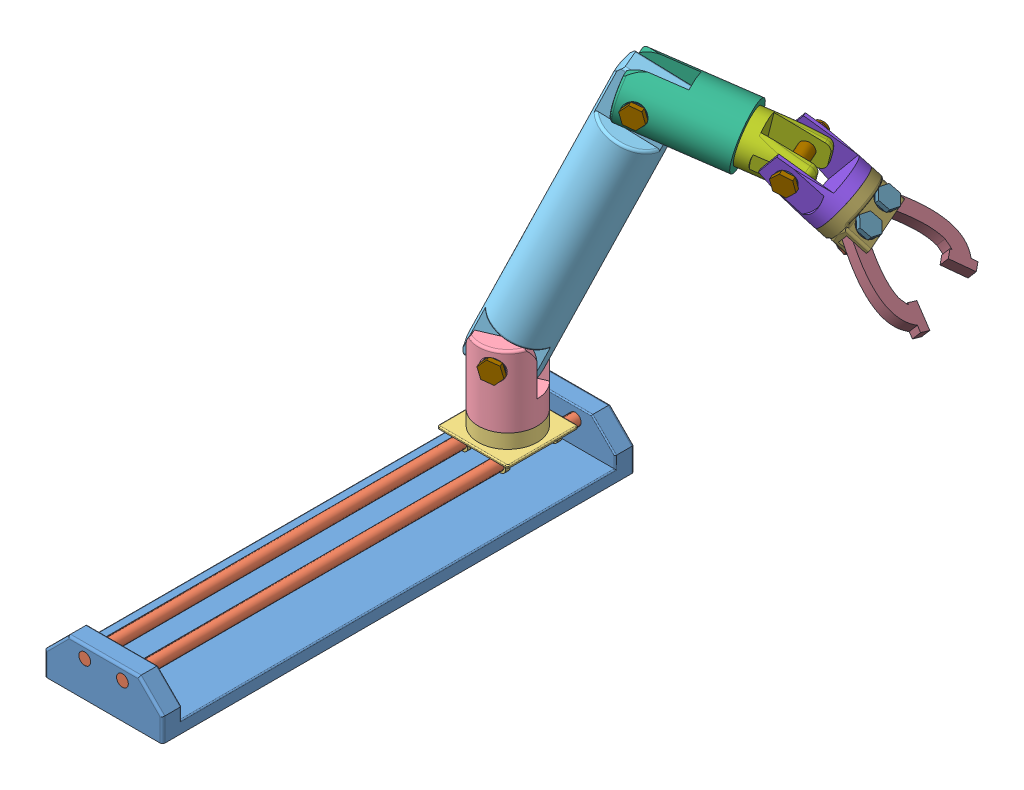
SolidWorks assembly Ensamble brazo, configuration Default. Lengths in mm.
Overall size (1624.77 1668.84 2538.17).
32 component instances, 14 part files, 63 mates.
Components (placement in the parent):
- Base brazo-1: Base brazo [Default] at (1021.9198 1533.4748 1057.1209) size (500 200 2000)
- Eje(s) de brazo-1: Eje(s) de brazo [Default] at (941.9198 1583.4748 1057.1209) x (0 0 1) z (-1 0 0) size (2000 49.9 49.9)
- Eje(s) de brazo-2: Eje(s) de brazo [Default] at (1101.9198 1583.4748 1057.1209) x (0 0 1) z (-1 0 0) size (2000 49.9 49.9)
- Plataforma brazo-1: Plataforma brazo [Default<As Machined>] at (1021.9198 1613.4748 1343.3712) x (1 0 0) z (0 1 0) size (300 300 189.9)
- brazo 1-1: brazo 1 [Default] at (1021.9198 1683.3748 1343.3712) x (-0.393554 0 -0.919302) z (0.919302 0 -0.393554) size (250 300.7 250)
- brazo 2-1: brazo 2 [Default] at (1232.2334 2435.9038 1253.3358) x (0.393554 0 0.919302) z (-0.843406 0.39787 0.361063) size (250 1300 250)
- brazo 3-1: brazo 3 [Default] at (1733.5814 2889.9427 1038.7083) x (0.393554 0 0.919302) z (-0.207876 -0.974099 0.088992) size (250 400.7 250)
- brazo 4-1: brazo 4 [Default] at (1733.4918 2889.9653 1038.7467) x (0.372278 -0.091536 0.923596) z (0.243938 0.969788 -0.002211) size (200 309.9 200)
- brazo 5-1: brazo 5 [Default] at (2012.2024 2740.2567 911.5681) x (0.372278 -0.091536 0.923596) z (-0.612701 -0.771708 0.170482) size (250 270 250)
- tornillo brazo-1: tornillo brazo [Default] at (1069.1463 1908.3748 1453.6874) x (-0.393554 0 -0.919302) z (0.249648 -0.962421 -0.106874) size (290 77.94 90)
- guasa-1: guasa [Default] at (1067.1785 1908.3748 1449.0909) x (0.393554 0 0.919302) z (-0.919302 0 0.393554) size (5 80 80)
- guasa-2: guasa [Default] at (974.6933 1908.3748 1233.055) x (0.393554 0 0.919302) z (0.092008 0.994979 -0.039389) size (5 80 80)
- tuerca-1: tuerca [Default] at (966.8223 1908.3748 1214.669) x (0.393554 0 0.919302) z (-0.919302 0 0.393554) size (20 77.94 90)
- guasa-3: guasa [Default] at (1487.8057 2963.4328 1269.0201) x (0.393554 0 0.919302) z (-0.919302 0 0.393554) size (5 80 80)
- guasa-4: guasa [Default] at (1395.3205 2963.4328 1052.9842) x (0.393554 0 0.919302) z (-0.919302 0 0.393554) size (5 80 80)
- tornillo brazo-2: tornillo brazo [Default] at (1489.7734 2963.4328 1273.6166) x (-0.393554 0 -0.919302) z (0.238294 -0.965821 -0.102014) size (290 77.94 90)
- tuerca-2: tuerca [Default] at (1387.4494 2963.4328 1034.5982) x (0.393554 0 0.919302) z (-0.919302 0 0.393554) size (20 77.94 90)
- guasa-5: guasa [Default] at (1931.1533 2840.3248 1073.2542) x (0.372278 -0.091536 0.923596) z (-0.926965 -0.086324 0.365081) size (5 80 80)
- guasa-6: guasa [Default] at (1847.3907 2860.9204 865.445) x (0.372278 -0.091536 0.923596) z (-0.926965 -0.086324 0.365081) size (5 80 80)
- tornillo brazo-3: tornillo brazo [Default] at (1933.0147 2839.8671 1077.8722) x (-0.372278 0.091536 -0.923596) z (-0.716975 -0.66028 0.223555) size (290 77.94 90)
- tuerca-3: tuerca [Default] at (1839.9451 2862.7511 846.9731) x (0.372278 -0.091536 0.923596) z (-0.926965 -0.086324 0.365081) size (20 77.94 90)
- brazo 6-1: brazo 6 [Default] at (2012.2722 2740.1937 911.5338) x (0.697142 -0.629355 -0.343374) z (-0.327412 0.146605 -0.933439) size (150 250 250)
- pinza-1: pinza [Default] at (2076.932 2703.6137 813.4735) x (-0.55206 0.358964 -0.752578) z (-0.637805 -0.763164 0.103854) size (170.38 402.12 47)
- pinza-2: pinza [Default] at (2089.5188 2648.6863 939.7017) x (-0.098861 0.214845 0.971632) z (0.637805 0.763164 -0.103854) size (170.38 402.12 47)
- guasa-7: guasa [Default] at (2092.8673 2722.681 810.8788) x (-0.637805 -0.763164 0.103854) z (-0.318903 0.138934 -0.937549) size (5 80 80)
- tuerca-4: tuerca [Default] at (2060.8175 2614.3439 944.3752) x (0.637805 0.763164 -0.103854) z (-0.246283 0.329846 0.911343) size (20 77.94 90)
- guasa-8: guasa [Default] at (2132.2418 2699.8065 932.7451) x (0.637805 0.763164 -0.103854) z (-0.246283 0.329846 0.911343) size (5 80 80)
- tuerca-5: tuerca [Default] at (2018.254 2633.4026 823.0281) x (0.637805 0.763164 -0.103854) z (-0.246283 0.329846 0.911343) size (20 77.94 90)
- guasa-9: guasa [Default] at (2073.5736 2629.6072 942.2981) x (0.637805 0.763164 -0.103854) z (-0.246283 0.329846 0.911343) size (5 80 80)
- guasa-10: guasa [Default] at (2031.0101 2648.6659 820.951) x (0.637805 0.763164 -0.103854) z (-0.246283 0.329846 0.911343) size (5 80 80)
- tornillo brazo 2-1: tornillo brazo 2 [Default] at (2092.8673 2722.681 810.8788) x (-0.637805 -0.763164 0.103854) z (0.044435 -0.171076 -0.984255) size (150 77.94 90)
- tornillo brazo 2-2: tornillo brazo 2 [Default] at (2135.4308 2703.6223 932.2259) x (-0.637805 -0.763164 0.103854) z (0.044435 -0.171076 -0.984255) size (150 77.94 90)
Mates (geometry in assembly coordinates):
- Concentric1: concentric anti-aligned: cylinder of Base brazo-1 through (941.9198 1583.4748 1057.1209) axis (0 0 1) radius 25; cylinder of Eje(s) de brazo-1 through (941.9198 1583.4748 3057.1209) axis (0 0 -1) radius 24.95
- Coincident2: coincident aligned: plane of Base brazo-1 through (1021.9198 1533.4748 3057.1209) normal (0 0 1); plane of Eje(s) de brazo-1 through (941.9198 1583.4748 3057.1209) normal (0 0 1)
- Concentric2: concentric anti-aligned: cylinder of Base brazo-1 through (1101.9198 1583.4748 1057.1209) axis (0 0 1) radius 25; cylinder of Eje(s) de brazo-2 through (1101.9198 1583.4748 3057.1209) axis (0 0 -1) radius 24.95
- Coincident3: coincident aligned: plane of Base brazo-1 through (1021.9198 1533.4748 3057.1209) normal (0 0 1); plane of Eje(s) de brazo-2 through (1101.9198 1583.4748 3057.1209) normal (0 0 1)
- Concentric3: concentric anti-aligned: cylinder of Eje(s) de brazo-2 through (1101.9198 1583.4748 3057.1209) axis (0 0 -1) radius 24.95; cylinder of Plataforma brazo-1 through (1101.9198 1583.4748 1193.3712) axis (0 0 1) radius 25
- Concentric4: concentric anti-aligned: cylinder of Eje(s) de brazo-1 through (941.9198 1583.4748 3057.1209) axis (0 0 -1) radius 24.95; cylinder of Plataforma brazo-1 through (941.9198 1583.4748 1193.3712) axis (0 0 1) radius 25
- Concentric5: concentric aligned: cylinder of Plataforma brazo-1 through (1021.9198 1743.3748 1343.3712) axis (0 -1 0) radius 50; cylinder of brazo 1-1 through (1021.9198 1743.3748 1343.3712) axis (0 -1 0) radius 50
- Coincident4: coincident anti-aligned: plane of Plataforma brazo-1 through (1021.9198 1743.3748 1343.3712) normal (0 1 0); plane of brazo 1-1 through (1021.9198 1743.3748 1343.3712) normal (0 -1 0)
- Concentric6: concentric anti-aligned: cylinder of brazo 1-1 through (1071.114 1908.3748 1458.2839) axis (-0.393554 0 -0.919302) radius 25; cylinder of brazo 2-1 through (972.7256 1908.3748 1228.4585) axis (0.393554 0 0.919302) radius 30
- Coincident5: coincident anti-aligned: plane of brazo 1-1 through (887.3294 1783.3748 1346.6004) normal (0.393554 0 0.919302); plane of brazo 2-1 through (1047.9625 2023.0551 1277.8332) normal (-0.393554 0 -0.919302)
- Concentric7: concentric aligned: cylinder of brazo 2-1 through (1393.3528 2963.4328 1048.3877) axis (0.393554 0 0.919302) radius 30; cylinder of brazo 3-1 through (1393.3528 2963.4328 1048.3877) axis (0.393554 0 0.919302) radius 25
- Coincident6: coincident anti-aligned: plane of brazo 2-1 through (1377.1489 2848.7526 1136.9082) normal (-0.393554 0 -0.919302); plane of brazo 3-1 through (1560.79 3056.9297 1058.2913) normal (0.393554 0 0.919302)
- Concentric8: concentric aligned: cylinder of brazo 3-1 through (1679.852 2903.5101 1061.7099) axis (0.89549 -0.226123 -0.38336) radius 50; cylinder of brazo 4-1 through (1679.852 2903.5101 1061.7099) axis (0.89549 -0.226123 -0.38336) radius 49.95
- Coincident7: coincident anti-aligned: plane of brazo 3-1 through (1679.852 2903.5101 1061.7099) normal (0.89549 -0.226123 -0.38336); plane of brazo 4-1 through (1679.852 2903.5101 1061.7099) normal (-0.89549 0.226123 0.38336)
- Concentric9: concentric aligned: cylinder of brazo 4-1 through (1852.9748 2859.5474 879.299) axis (0.372278 -0.091536 0.923596) radius 30; cylinder of brazo 5-1 through (1843.6679 2861.8358 856.2091) axis (0.372278 -0.091536 0.923596) radius 30
- Coincident8: coincident anti-aligned: plane of brazo 4-1 through (1925.5691 2841.6978 1059.4003) normal (0.372278 -0.091536 0.923596); plane of brazo 5-1 through (2089.2994 2859.492 995.1683) normal (-0.372278 0.091536 -0.923596)
- Concentric12: concentric anti-aligned: cylinder of brazo 1-1 through (1071.114 1908.3748 1458.2839) axis (-0.393554 0 -0.919302) radius 25; cylinder of tornillo brazo-1 through (962.8867 1908.3748 1205.476) axis (0.393554 0 0.919302) radius 29.95
- Concentric13: concentric aligned: cylinder of brazo 1-1 through (1071.114 1908.3748 1458.2839) axis (-0.393554 0 -0.919302) radius 25; cylinder of guasa-1 through (1069.1463 1908.3748 1453.6874) axis (-0.393554 0 -0.919302) radius 25
- Coincident12: coincident anti-aligned: plane of brazo 1-1 through (1067.1785 1908.3748 1449.0909) normal (0.393554 0 0.919302); plane of guasa-1 through (1067.1785 1908.3748 1449.0909) normal (-0.393554 0 -0.919302)
- Coincident13: coincident anti-aligned: plane of tornillo brazo-1 through (1069.1463 1908.3748 1453.6874) normal (-0.393554 0 -0.919302); plane of guasa-1 through (1069.1463 1908.3748 1453.6874) normal (0.393554 0 0.919302)
- Concentric14: concentric anti-aligned: cylinder of tornillo brazo-1 through (962.8867 1908.3748 1205.476) axis (0.393554 0 0.919302) radius 29.95; cylinder of guasa-2 through (976.6611 1908.3748 1237.6515) axis (-0.393554 0 -0.919302) radius 25
- Coincident14: coincident anti-aligned: plane of brazo 1-1 through (976.6611 1908.3748 1237.6515) normal (-0.393554 0 -0.919302); plane of guasa-2 through (976.6611 1908.3748 1237.6515) normal (0.393554 0 0.919302)
- Concentric15: concentric anti-aligned: cylinder of tornillo brazo-1 through (962.8867 1908.3748 1205.476) axis (0.393554 0 0.919302) radius 29.95; cylinder of tuerca-1 through (974.6933 1908.3748 1233.055) axis (-0.393554 0 -0.919302) radius 30
- Coincident15: coincident anti-aligned: plane of guasa-2 through (974.6933 1908.3748 1233.055) normal (-0.393554 0 -0.919302); plane of tuerca-1 through (974.6933 1908.3748 1233.055) normal (0.393554 0 0.919302)
- Concentric16: concentric anti-aligned: cylinder of brazo 3-1 through (1393.3528 2963.4328 1048.3877) axis (0.393554 0 0.919302) radius 25; cylinder of guasa-3 through (1489.7734 2963.4328 1273.6166) axis (-0.393554 0 -0.919302) radius 25
- Coincident16: coincident anti-aligned: plane of brazo 3-1 through (1487.8057 2963.4328 1269.0201) normal (0.393554 0 0.919302); plane of guasa-3 through (1487.8057 2963.4328 1269.0201) normal (-0.393554 0 -0.919302)
- Concentric17: concentric anti-aligned: cylinder of brazo 3-1 through (1393.3528 2963.4328 1048.3877) axis (0.393554 0 0.919302) radius 25; cylinder of guasa-4 through (1397.2883 2963.4328 1057.5807) axis (-0.393554 0 -0.919302) radius 25
- Coincident17: coincident anti-aligned: plane of brazo 3-1 through (1397.2883 2963.4328 1057.5807) normal (-0.393554 0 -0.919302); plane of guasa-4 through (1397.2883 2963.4328 1057.5807) normal (0.393554 0 0.919302)
- Concentric18: concentric aligned: cylinder of brazo 3-1 through (1393.3528 2963.4328 1048.3877) axis (0.393554 0 0.919302) radius 25; cylinder of tornillo brazo-2 through (1383.5139 2963.4328 1025.4051) axis (0.393554 0 0.919302) radius 29.95
- Coincident18: coincident anti-aligned: plane of guasa-3 through (1489.7734 2963.4328 1273.6166) normal (0.393554 0 0.919302); plane of tornillo brazo-2 through (1489.7734 2963.4328 1273.6166) normal (-0.393554 0 -0.919302)
- Concentric19: concentric anti-aligned: cylinder of tornillo brazo-2 through (1383.5139 2963.4328 1025.4051) axis (0.393554 0 0.919302) radius 29.95; cylinder of tuerca-2 through (1395.3205 2963.4328 1052.9842) axis (-0.393554 0 -0.919302) radius 30
- Coincident19: coincident anti-aligned: plane of guasa-4 through (1395.3205 2963.4328 1052.9842) normal (-0.393554 0 -0.919302); plane of tuerca-2 through (1395.3205 2963.4328 1052.9842) normal (0.393554 0 0.919302)
- Concentric20: concentric aligned: cylinder of brazo 4-1 through (1852.9748 2859.5474 879.299) axis (0.372278 -0.091536 0.923596) radius 30; cylinder of tornillo brazo-3 through (1832.4995 2864.5819 828.5012) axis (0.372278 -0.091536 0.923596) radius 29.95
- Concentric22: concentric anti-aligned: cylinder of brazo 4-1 through (1852.9748 2859.5474 879.299) axis (0.372278 -0.091536 0.923596) radius 30; cylinder of guasa-5 through (1933.0147 2839.8671 1077.8722) axis (-0.372278 0.091536 -0.923596) radius 25
- Coincident20: coincident anti-aligned: plane of brazo 5-1 through (1931.1533 2840.3248 1073.2542) normal (0.372278 -0.091536 0.923596); plane of guasa-5 through (1931.1533 2840.3248 1073.2542) normal (-0.372278 0.091536 -0.923596)
- Coincident21: coincident anti-aligned: plane of guasa-5 through (1933.0147 2839.8671 1077.8722) normal (0.372278 -0.091536 0.923596); plane of tornillo brazo-3 through (1933.0147 2839.8671 1077.8722) normal (-0.372278 0.091536 -0.923596)
- Concentric23: concentric anti-aligned: cylinder of guasa-6 through (1849.2521 2860.4627 870.063) axis (-0.372278 0.091536 -0.923596) radius 25; cylinder of tornillo brazo-3 through (1832.4995 2864.5819 828.5012) axis (0.372278 -0.091536 0.923596) radius 29.95
- Coincident22: coincident anti-aligned: plane of brazo 5-1 through (1849.2521 2860.4627 870.063) normal (-0.372278 0.091536 -0.923596); plane of guasa-6 through (1849.2521 2860.4627 870.063) normal (0.372278 -0.091536 0.923596)
- Concentric24: concentric anti-aligned: cylinder of tornillo brazo-3 through (1832.4995 2864.5819 828.5012) axis (0.372278 -0.091536 0.923596) radius 29.95; cylinder of tuerca-3 through (1847.3907 2860.9204 865.445) axis (-0.372278 0.091536 -0.923596) radius 30
- Coincident23: coincident anti-aligned: plane of guasa-6 through (1847.3907 2860.9204 865.445) normal (-0.372278 0.091536 -0.923596); plane of tuerca-3 through (1847.3907 2860.9204 865.445) normal (0.372278 -0.091536 0.923596)
- Concentric25: concentric aligned: cylinder of brazo 5-1 through (2026.1453 2727.6696 904.7006) axis (-0.697142 0.629355 0.343374) radius 59.95; cylinder of brazo 6-1 through (2026.1453 2727.6696 904.7006) axis (-0.697142 0.629355 0.343374) radius 60
- Coincident24: coincident anti-aligned: plane of brazo 5-1 through (2026.1453 2727.6696 904.7006) normal (0.697142 -0.629355 -0.343374); plane of brazo 6-1 through (2026.1453 2727.6696 904.7006) normal (-0.697142 0.629355 0.343374)
- Concentric26: concentric anti-aligned: cylinder of brazo 6-1 through (2089.6782 2718.8651 811.3981) axis (-0.637805 -0.763164 0.103854) radius 30; cylinder of pinza-1 through (2046.9552 2667.745 818.3547) axis (0.637805 0.763164 -0.103854) radius 30
- Coincident25: coincident anti-aligned: plane of brazo 6-1 through (2005.1621 2696.536 773.2574) normal (0.637805 0.763164 -0.103854); plane of pinza-1 through (2046.9552 2667.745 818.3547) normal (-0.637805 -0.763164 0.103854)
- Concentric27: concentric aligned: cylinder of brazo 6-1 through (2132.2418 2699.8065 932.7451) axis (-0.637805 -0.763164 0.103854) radius 30; cylinder of pinza-2 through (2119.4956 2684.555 934.8206) axis (-0.637805 -0.763164 0.103854) radius 30
- Coincident26: coincident anti-aligned: plane of brazo 6-1 through (2005.1621 2696.536 773.2574) normal (0.637805 0.763164 -0.103854); plane of pinza-2 through (2089.5188 2648.6863 939.7017) normal (-0.637805 -0.763164 0.103854)
- Concentric28: concentric anti-aligned: cylinder of brazo 6-1 through (2089.6782 2718.8651 811.3981) axis (-0.637805 -0.763164 0.103854) radius 30; cylinder of guasa-7 through (2089.6782 2718.8651 811.3981) axis (0.637805 0.763164 -0.103854) radius 25
- Coincident27: coincident anti-aligned: plane of brazo 6-1 through (2103.6565 2697.3078 738.8309) normal (0.637805 0.763164 -0.103854); plane of guasa-7 through (2089.6782 2718.8651 811.3981) normal (-0.637805 -0.763164 0.103854)
- Coincident28: coincident anti-aligned: plane of brazo 6-1 through (2048.1773 2630.9244 747.8646) normal (-0.637805 -0.763164 0.103854); plane of guasa-10 through (2034.1991 2652.4817 820.4318) normal (0.637805 0.763164 -0.103854)
- Concentric29: concentric aligned: cylinder of brazo 6-1 through (2089.6782 2718.8651 811.3981) axis (-0.637805 -0.763164 0.103854) radius 30; cylinder of guasa-10 through (2034.1991 2652.4817 820.4318) axis (-0.637805 -0.763164 0.103854) radius 25
- Concentric32: concentric anti-aligned: cylinder of brazo 6-1 through (2089.6782 2718.8651 811.3981) axis (-0.637805 -0.763164 0.103854) radius 30; cylinder of tornillo brazo 2-1 through (2009.9526 2623.4696 824.3798) axis (0.637805 0.763164 -0.103854) radius 29.95
- Coincident30: coincident anti-aligned: plane of guasa-7 through (2092.8673 2722.681 810.8788) normal (0.637805 0.763164 -0.103854); plane of tornillo brazo 2-1 through (2092.8673 2722.681 810.8788) normal (-0.637805 -0.763164 0.103854)
- Concentric33: concentric anti-aligned: cylinder of tuerca-5 through (2031.0101 2648.6659 820.951) axis (-0.637805 -0.763164 0.103854) radius 30; cylinder of tornillo brazo 2-1 through (2009.9526 2623.4696 824.3798) axis (0.637805 0.763164 -0.103854) radius 29.95
- Coincident31: coincident anti-aligned: plane of tuerca-5 through (2031.0101 2648.6659 820.951) normal (0.637805 0.763164 -0.103854); plane of guasa-10 through (2031.0101 2648.6659 820.951) normal (-0.637805 -0.763164 0.103854)
- Coincident32: coincident anti-aligned: plane of brazo 6-1 through (2048.1773 2630.9244 747.8646) normal (-0.637805 -0.763164 0.103854); plane of guasa-9 through (2076.7627 2633.423 941.7788) normal (0.637805 0.763164 -0.103854)
- Concentric34: concentric aligned: cylinder of brazo 6-1 through (2132.2418 2699.8065 932.7451) axis (-0.637805 -0.763164 0.103854) radius 30; cylinder of guasa-9 through (2076.7627 2633.423 941.7788) axis (-0.637805 -0.763164 0.103854) radius 25
- Coincident33: coincident anti-aligned: plane of brazo 6-1 through (2103.6565 2697.3078 738.8309) normal (0.637805 0.763164 -0.103854); plane of guasa-8 through (2132.2418 2699.8065 932.7451) normal (-0.637805 -0.763164 0.103854)
- Concentric35: concentric aligned: cylinder of pinza-2 through (2119.4956 2684.555 934.8206) axis (-0.637805 -0.763164 0.103854) radius 30; cylinder of guasa-8 through (2135.4308 2703.6223 932.2259) axis (-0.637805 -0.763164 0.103854) radius 25
- Concentric36: concentric anti-aligned: cylinder of brazo 6-1 through (2132.2418 2699.8065 932.7451) axis (-0.637805 -0.763164 0.103854) radius 30; cylinder of tornillo brazo 2-2 through (2052.5162 2604.411 945.7269) axis (0.637805 0.763164 -0.103854) radius 29.95
- Coincident34: coincident anti-aligned: plane of guasa-8 through (2135.4308 2703.6223 932.2259) normal (0.637805 0.763164 -0.103854); plane of tornillo brazo 2-2 through (2135.4308 2703.6223 932.2259) normal (-0.637805 -0.763164 0.103854)
- Concentric37: concentric anti-aligned: cylinder of tuerca-4 through (2073.5736 2629.6072 942.2981) axis (-0.637805 -0.763164 0.103854) radius 30; cylinder of tornillo brazo 2-2 through (2052.5162 2604.411 945.7269) axis (0.637805 0.763164 -0.103854) radius 29.95
- Coincident35: coincident anti-aligned: plane of tuerca-4 through (2073.5736 2629.6072 942.2981) normal (0.637805 0.763164 -0.103854); plane of guasa-9 through (2073.5736 2629.6072 942.2981) normal (-0.637805 -0.763164 0.103854)
- LimitDistance1: limit distance = 1483.7497 mm anti-aligned: plane of Base brazo-1 through (1771.9198 1633.4748 2977.1209) normal (0 0 -1); plane of Plataforma brazo-1 through (881.9198 1623.4748 1493.3712) normal (0 0 1)
